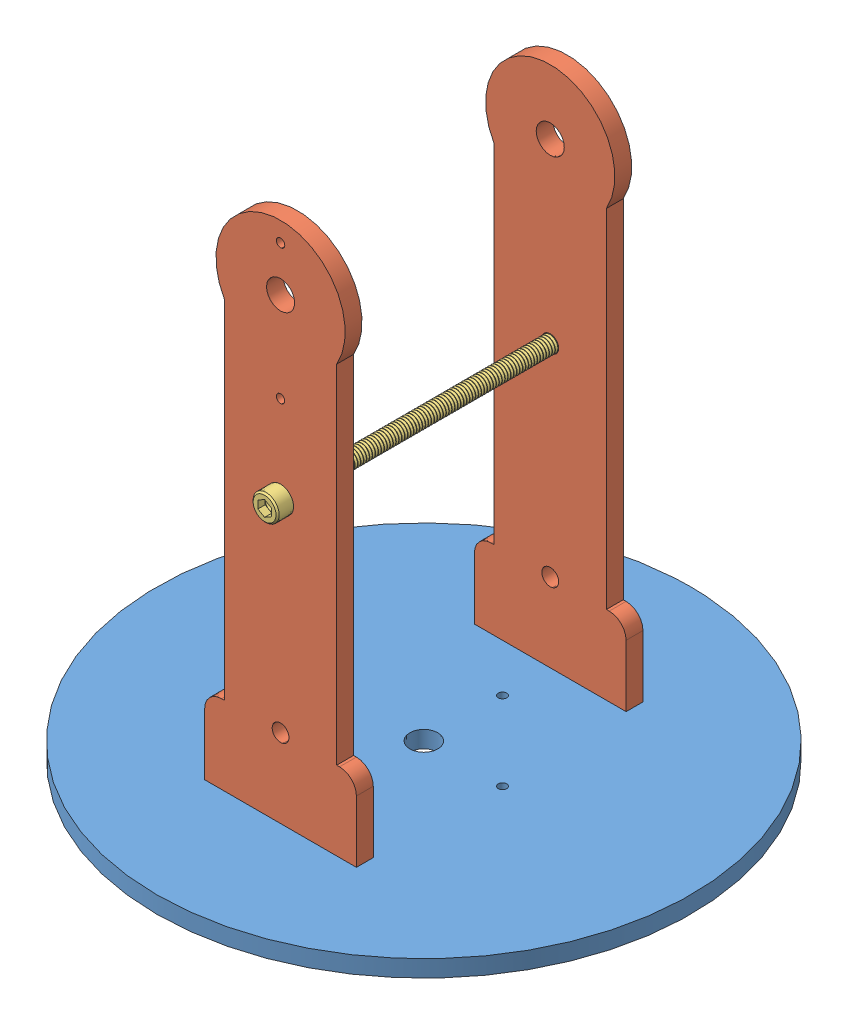
SolidWorks assembly link_1_littleRobot, configuration Predeterminado. Lengths in mm.
Overall size (95 96 95).
4 component instances, 3 part files, 57 mates.
Components (placement in the parent):
- H_pieza_arm_robot_v0-1: H_pieza_arm_robot_v0 [Predeterminado] x (0 0 -1) z (0 1 0) size (95 95 3)
- D_pieza_arm_robot_v0-1: D_pieza_arm_robot_v0 [piexa_motor_leva] at (0 84.5 25.5) x (-1 0 0) z (0 0 -1) size (27 96 3)
- D_pieza_arm_robot_v0-2: D_pieza_arm_robot_v0 [Predeterminado] at (0 84.5 -22.5) x (-1 0 0) z (0 0 -1) size (27 96 3)
- socket head cap screw_ai-6: socket head cap screw_ai [HX-SHCS 0.112-48x2.25x2.25-S] at (0 53 28.3448) x (0 0 -1) z (1 0 0) size (59.99 4.65 4.65)
Mates (geometry in assembly coordinates):
- Coincidente6: coincident anti-aligned: plane of H_pieza_arm_robot_v0-1 through (2.5 0 25.5) normal (0 0 -1); plane of D_pieza_arm_robot_v0-1 through (0 84.5 25.5) normal (0 0 1)
- Coincidente7: coincident anti-aligned: plane of H_pieza_arm_robot_v0-1 through (10.5 0 22.5) normal (-1 0 0); plane of D_pieza_arm_robot_v0-1 through (10.5 3 25.5) normal (1 0 0)
- Coincidente8: coincident anti-aligned: plane of H_pieza_arm_robot_v0-1 through (0 3 0) normal (0 1 0); plane of D_pieza_arm_robot_v0-1 through (0 3 22.5) normal (0 -1 0)
- Coincidente9: coincident anti-aligned: plane of H_pieza_arm_robot_v0-1 through (-10.5 0 -22.5) normal (1 0 0); plane of D_pieza_arm_robot_v0-2 through (-10.5 3 -22.5) normal (-1 0 0)
- Coincidente10: coincident anti-aligned: plane of H_pieza_arm_robot_v0-1 through (-10.5 0 -25.5) normal (0 0 1); plane of D_pieza_arm_robot_v0-2 through (0 84.5 -25.5) normal (0 0 -1)
- Coincidente12: coincident anti-aligned: plane of H_pieza_arm_robot_v0-1 through (0 3 0) normal (0 1 0); plane of D_pieza_arm_robot_v0-2 through (0 3 -25.5) normal (0 -1 0)
- Coincidente13: coincident anti-aligned: plane of C_pieza_arm_robot_v0-1 through (56.75 126.5 12) normal (0 0 -1); plane of Servomoteur Futuba S3003-2/Couvercle supérieure-1 through (78.5 131.5 12) normal (0 0 1)
- Concéntrica6: concentric anti-aligned: cylinder of C_pieza_arm_robot_v0-1 through (129 121.5 12) axis (0 0 1) radius 2; cylinder of Servomoteur Futuba S3003-2/Couvercle supérieure-1 through (129 121.5 12) axis (0 0 -1) radius 2
- Concéntrica7: concentric anti-aligned: cylinder of C_pieza_arm_robot_v0-1 through (129 131.5 12) axis (0 0 1) radius 2; cylinder of Servomoteur Futuba S3003-2/Couvercle supérieure-1 through (129 131.5 12) axis (0 0 -1) radius 2
- Concéntrica11: concentric anti-aligned: cylinder of D_pieza_arm_robot_v0-2 through (0 84.5 -22.5) axis (0 0 -1) radius 2.5; cylinder of E_pieza_arm_robot_v0-1 through (0 126.5 -20.5) axis (0 0 1) radius 1.5
- Distancia4: distance = 2 mm anti-aligned: plane of E_pieza_arm_robot_v0-1 through (56.75 126.5 -20.5) normal (0 0 -1); plane of D_pieza_arm_robot_v0-2 through (0 84.5 -22.5) normal (0 0 1)
- Paralelo3: parallel aligned: plane of C_pieza_arm_robot_v0-1 through (41.75 116.5 15) normal (0 -1 0); plane of E_pieza_arm_robot_v0-1 through (56.75 116.5 -17.5) normal (0 -1 0)
- Concéntrica16: concentric anti-aligned: cylinder of Servomoteur Futuba S3003-2/Axe-1 through (113.5 126.5 8.5) axis (0 0 1) radius 2.5; cylinder of F_pieza_arm_robot_v0-1 through (113.5 126.5 26) axis (0 0 -1) radius 2.5
- Distancia6: distance = 8 mm anti-aligned: plane of F_pieza_arm_robot_v0-1 through (113.5 126.5 23) normal (0 0 -1); plane of C_pieza_arm_robot_v0-1 through (56.75 126.5 15) normal (0 0 1)
- Concéntrica17: concentric anti-aligned: cylinder of E_pieza_arm_robot_v0-1 through (113.5 126.5 -20.5) axis (0 0 1) radius 1.5; cylinder of F_pieza_arm_robot_v0-2 through (113.5 126.5 -22.5) axis (0 0 -1) radius 2.5
- Distancia7: distance = 2 mm anti-aligned: plane of F_pieza_arm_robot_v0-2 through (113.5 126.5 -22.5) normal (0 0 1); plane of E_pieza_arm_robot_v0-1 through (56.75 126.5 -20.5) normal (0 0 -1)
- Coincidente21: coincident anti-aligned: plane of F_pieza_arm_robot_v0-1 through (155 124.95 26) normal (0 1 0); plane of G_pieza_arm_robot_v0-1 through (158.5 124.95 0.75) normal (0 -1 0)
- Coincidente23: coincident aligned: plane of F_pieza_arm_robot_v0-1 through (113.5 126.5 26) normal (0 0 1); plane of G_pieza_arm_robot_v0-1 through (158.5 127.95 26) normal (0 0 1)
- Coincidente24: coincident anti-aligned: plane of F_pieza_arm_robot_v0-1 through (162 124.95 26) normal (-1 0 0); plane of G_pieza_arm_robot_v0-1 through (162 127.95 0.75) normal (1 0 0)
- Coincidente25: coincident anti-aligned: plane of F_pieza_arm_robot_v0-2 through (155 124.95 -22.5) normal (0 1 0); plane of G_pieza_arm_robot_v0-1 through (158.5 124.95 0.75) normal (0 -1 0)
- Concéntrica30: concentric anti-aligned: cylinder of D_pieza_arm_robot_v0-1 through (0 53 25.5) axis (0 0 -1) radius 1.5; cylinder of socket head cap screw_ai-6 through (0 53 60.0948) axis (0 0 1) radius 2.3241
- Coincidente35: coincident anti-aligned: plane of D_pieza_arm_robot_v0-1 through (0 84.5 25.5) normal (0 0 1); plane of socket head cap screw_ai-6 through (0 55.3241 25.5) normal (0 0 -1)
- Concéntrica31: concentric aligned: cylinder of C_pieza_arm_robot_v0-1 through (41.75 126.5 12) axis (0 0 1) radius 1.5; cylinder of socket head cap screw_ai-7 through (64.7787 129.0283 0.1988) axis (0.763622 0 0.645663) radius 2.3241
- Coincidente36: coincident anti-aligned: plane of C_pieza_arm_robot_v0-1 through (56.75 126.5 15) normal (0 0 1); plane of socket head cap screw_ai-7 through (38.3613 131.3524 -22.1378) normal (-0.763622 0 -0.645663)
- Concéntrica32: concentric aligned: cylinder of C_pieza_arm_robot_v0-1 through (71.75 126.5 12) axis (0 0 1) radius 1.5; cylinder of socket head cap screw_ai-9 through (84.113 130.8451 -22.6678) axis (0.763622 0 0.645663) radius 2.3241
- Coincidente38: coincident anti-aligned: plane of C_pieza_arm_robot_v0-1 through (56.75 126.5 15) normal (0 0 1); plane of socket head cap screw_ai-9 through (57.6956 133.1692 -45.0044) normal (-0.763622 0 -0.645663)
- Concéntrica33: concentric anti-aligned: cylinder of F_pieza_arm_robot_v0-1 through (145 126.5 26) axis (0 0 -1) radius 1.5; cylinder of socket head cap screw_ai-10 through (138.4716 144.3994 -69.9206) axis (0.763622 0 0.645663) radius 2.3241
- Coincidente39: coincident anti-aligned: plane of F_pieza_arm_robot_v0-1 through (113.5 126.5 26) normal (0 0 1); plane of socket head cap screw_ai-10 through (112.0542 146.7235 -92.2572) normal (-0.763622 0 -0.645663)
- Concéntrica34: concentric aligned: cylinder of C_pieza_arm_robot_v0-1 through (41.75 126.5 12) axis (0 0 1) radius 1.5; cylinder of socket head cap screw_ai-11 through (41.75 126.5 49.5948) axis (0 0 1) radius 2.3241
- Coincidente40: coincident anti-aligned: plane of C_pieza_arm_robot_v0-1 through (56.75 126.5 15) normal (0 0 1); plane of socket head cap screw_ai-11 through (41.75 128.8241 15) normal (0 0 -1)
- Concéntrica35: concentric aligned: cylinder of C_pieza_arm_robot_v0-1 through (71.75 126.5 12) axis (0 0 1) radius 1.5; cylinder of socket head cap screw_ai-12 through (71.75 126.5 49.5948) axis (0 0 1) radius 2.3241
- Coincidente41: coincident anti-aligned: plane of C_pieza_arm_robot_v0-1 through (56.75 126.5 15) normal (0 0 1); plane of socket head cap screw_ai-12 through (71.75 128.8241 15) normal (0 0 -1)
- Concéntrica36: concentric anti-aligned: cylinder of F_pieza_arm_robot_v0-1 through (145 126.5 26) axis (0 0 -1) radius 1.5; cylinder of socket head cap screw_ai-13 through (145 126.5 60.5948) axis (0 0 1) radius 2.3241
- Coincidente42: coincident anti-aligned: plane of F_pieza_arm_robot_v0-1 through (113.5 126.5 26) normal (0 0 1); plane of socket head cap screw_ai-13 through (145 128.8241 26) normal (0 0 -1)
- Concéntrica37: concentric aligned: cylinder of C_pieza_arm_robot_v0-1 through (35 131.5 12) axis (0 0 1) radius 2; cylinder of socket head cap screw_ai-14 through (35 131.5 50.2552) axis (0 0 1) radius 2.8702
- Coincidente43: coincident anti-aligned: plane of C_pieza_arm_robot_v0-1 through (56.75 126.5 15) normal (0 0 1); plane of socket head cap screw_ai-14 through (35 134.3702 15) normal (0 0 -1)
- Concéntrica38: concentric aligned: cylinder of C_pieza_arm_robot_v0-1 through (35 121.5 12) axis (0 0 1) radius 2; cylinder of socket head cap screw_ai-15 through (35 121.5 50.2552) axis (0 0 1) radius 2.8702
- Coincidente44: coincident anti-aligned: plane of C_pieza_arm_robot_v0-1 through (56.75 126.5 15) normal (0 0 1); plane of socket head cap screw_ai-15 through (35 124.3702 15) normal (0 0 -1)
- Concéntrica39: concentric aligned: cylinder of C_pieza_arm_robot_v0-1 through (-15.5 131.5 12) axis (0 0 1) radius 2; cylinder of socket head cap screw_ai-16 through (-15.5 131.5 50.2552) axis (0 0 1) radius 2.8702
- Coincidente45: coincident anti-aligned: plane of C_pieza_arm_robot_v0-1 through (56.75 126.5 15) normal (0 0 1); plane of socket head cap screw_ai-16 through (-15.5 134.3702 15) normal (0 0 -1)
- Concéntrica40: concentric aligned: cylinder of C_pieza_arm_robot_v0-1 through (-15.5 121.5 12) axis (0 0 1) radius 2; cylinder of socket head cap screw_ai-17 through (-15.5 121.5 50.2552) axis (0 0 1) radius 2.8702
- Coincidente46: coincident anti-aligned: plane of C_pieza_arm_robot_v0-1 through (56.75 126.5 15) normal (0 0 1); plane of socket head cap screw_ai-17 through (-15.5 124.3702 15) normal (0 0 -1)
- Concéntrica41: concentric aligned: cylinder of C_pieza_arm_robot_v0-1 through (78.5 131.5 12) axis (0 0 1) radius 2; cylinder of socket head cap screw_ai-18 through (78.5 131.5 50.2552) axis (0 0 1) radius 2.8702
- Coincidente47: coincident anti-aligned: plane of C_pieza_arm_robot_v0-1 through (56.75 126.5 15) normal (0 0 1); plane of socket head cap screw_ai-18 through (78.5 134.3702 15) normal (0 0 -1)
- Concéntrica42: concentric aligned: cylinder of C_pieza_arm_robot_v0-1 through (78.5 121.5 12) axis (0 0 1) radius 2; cylinder of socket head cap screw_ai-19 through (78.5 121.5 50.2552) axis (0 0 1) radius 2.8702
- Coincidente48: coincident anti-aligned: plane of C_pieza_arm_robot_v0-1 through (56.75 126.5 15) normal (0 0 1); plane of socket head cap screw_ai-19 through (78.5 124.3702 15) normal (0 0 -1)
- Concéntrica43: concentric aligned: cylinder of C_pieza_arm_robot_v0-1 through (129 131.5 12) axis (0 0 1) radius 2; cylinder of socket head cap screw_ai-20 through (129 131.5 50.2552) axis (0 0 1) radius 2.8702
- Coincidente49: coincident anti-aligned: plane of C_pieza_arm_robot_v0-1 through (56.75 126.5 15) normal (0 0 1); plane of socket head cap screw_ai-20 through (129 134.3702 15) normal (0 0 -1)
- Concéntrica44: concentric aligned: cylinder of C_pieza_arm_robot_v0-1 through (129 121.5 12) axis (0 0 1) radius 2; cylinder of socket head cap screw_ai-21 through (129 121.5 50.2552) axis (0 0 1) radius 2.8702
- Coincidente50: coincident anti-aligned: plane of C_pieza_arm_robot_v0-1 through (56.75 126.5 15) normal (0 0 1); plane of socket head cap screw_ai-21 through (129 124.3702 15) normal (0 0 -1)
- Coincidente55: coincident anti-aligned: plane of G_pieza_arm_robot_v0-1 through (158.5 127.95 0.75) normal (0 1 0); plane of Towerpro Micro Servo 9g-1 through (165 127.95 -14.5) normal (0 -1 0)
- Distancia8: distance = 15 mm aligned: plane of Towerpro Micro Servo 9g-1 through (165.5 144.45 11.75) normal (1 0 0); plane of G_pieza_arm_robot_v0-1 through (180.5 127.95 0.75) normal (1 0 0)
- Distancia9: distance = 6 mm anti-aligned: plane of Towerpro Micro Servo 9g-1 through (160.2 127.95 17) normal (0 0 1); plane of F_pieza_arm_robot_v0-1 through (113.5 126.5 23) normal (0 0 -1)
- Paralelo9: parallel aligned: plane of C_pieza_arm_robot_v0-1 through (41.75 136.5 15) normal (0 1 0); plane of F_pieza_arm_robot_v0-1 through (113.5 133 23) normal (0 1 0)
- Coincidente56: coincident anti-aligned: plane of H_pieza_arm_robot_v0-1 through (0 0 0) normal (0 0 -1)
- Coincidente57: coincident anti-aligned: plane of H_pieza_arm_robot_v0-1 through (0 0 0) normal (0 -1 0)
- Coincidente58: coincident anti-aligned: plane of H_pieza_arm_robot_v0-1 through (0 0 0) normal (-1 0 0)
